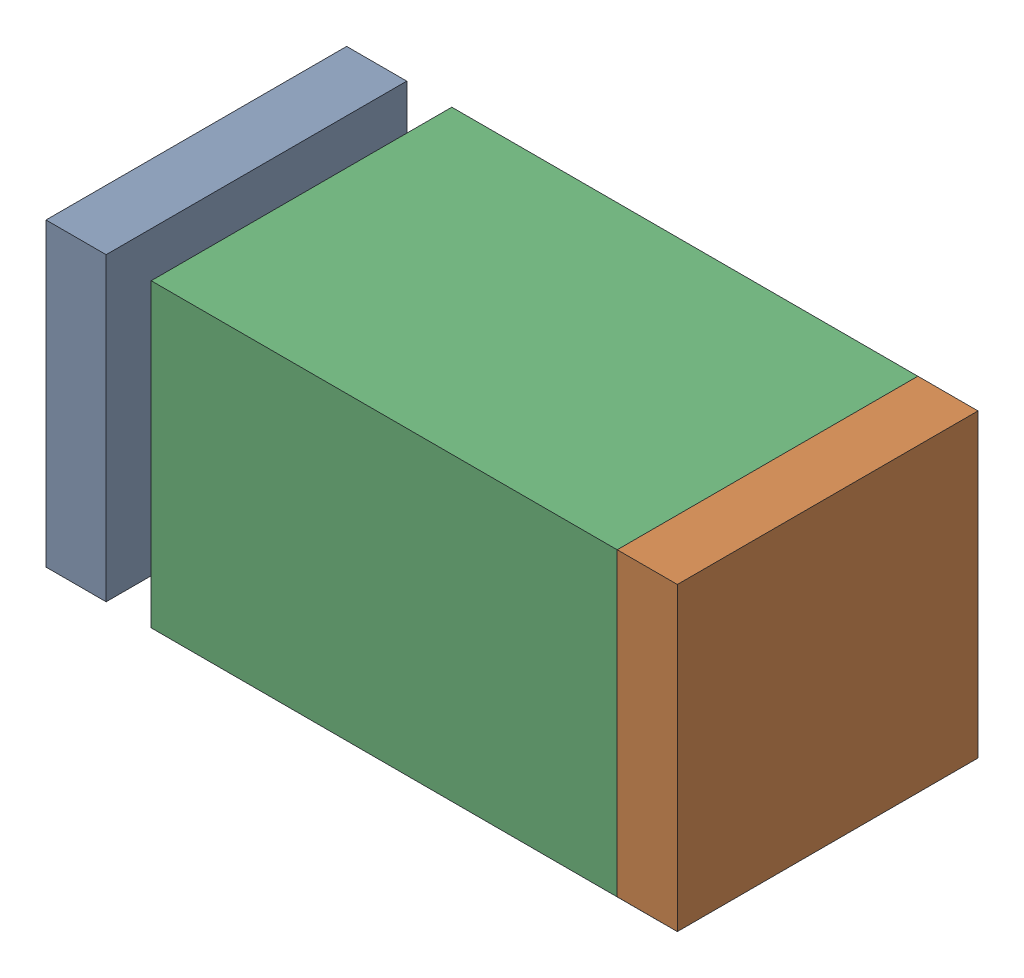
SolidWorks assembly C26, configuration Default. Lengths in mm.
Overall size (1.05 0.5 0.5).
6 component instances, 2 part files, 0 mates.
Components (placement in the parent):
- 810156080-1: 810156080 [Default] at (130.5 25.85 0) size (0.1 0.5 0.5)
  - Extruded_5-1: Extruded_5 [Default] at origin size (0.1 0.5 0.5)
- 810156080-2: 810156080 [Default] at (131.45 25.85 0) size (0.1 0.5 0.5)
  - Extruded_5-1: Extruded_5 [Default] at origin size (0.1 0.5 0.5)
- 810156208-1: 810156208 [Default] at (131.0499 25.8499 0) size (0.85 0.5 0.5)
  - Extruded_17-1: Extruded_17 [Default] at origin size (0.85 0.5 0.5)
